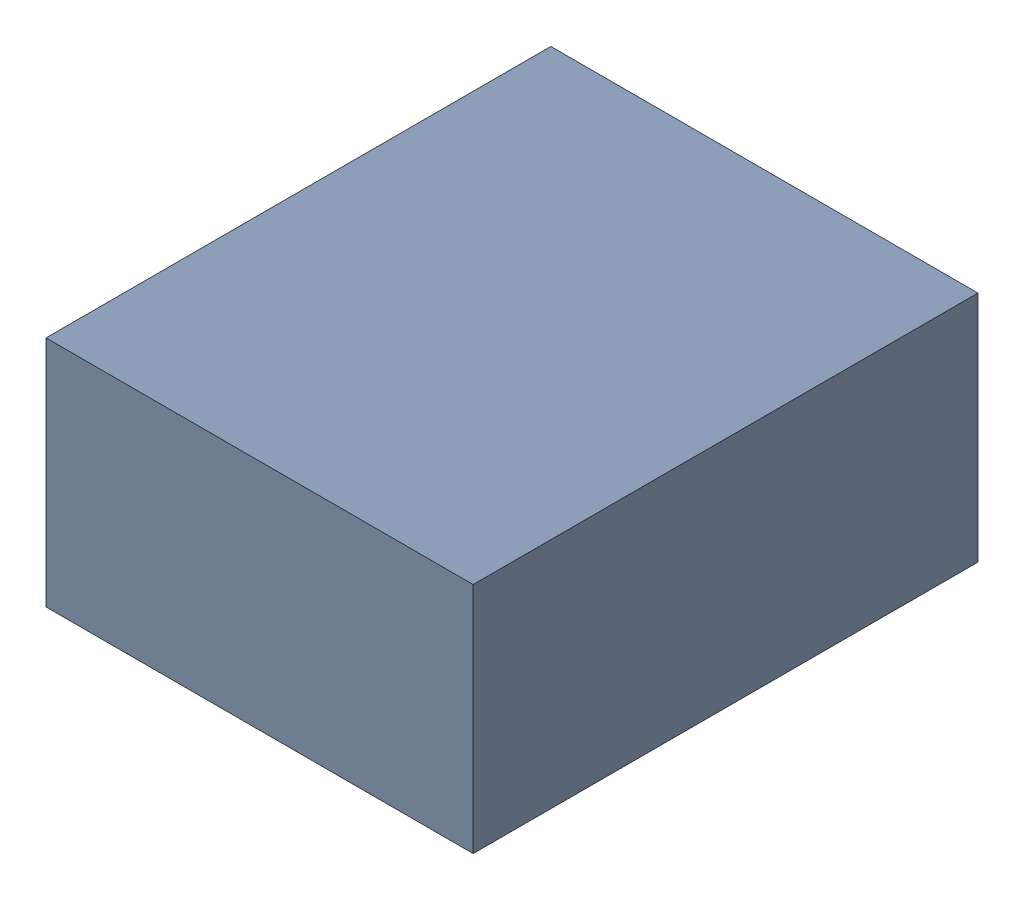
SolidWorks assembly C29_TDA1, configuration Standard. Lengths in mm.
Overall size (1.1 0.6 1.3).
2 component instances, 1 part files, 0 mates.
Components (placement in the parent):
- 885542240-1: 885542240 [Standard] at (-0.42 58.04 0) size (1.1 0.6 1.3)
  - Extruded_28-1: Extruded_28 [Standard] at origin size (1.1 0.6 1.3)
